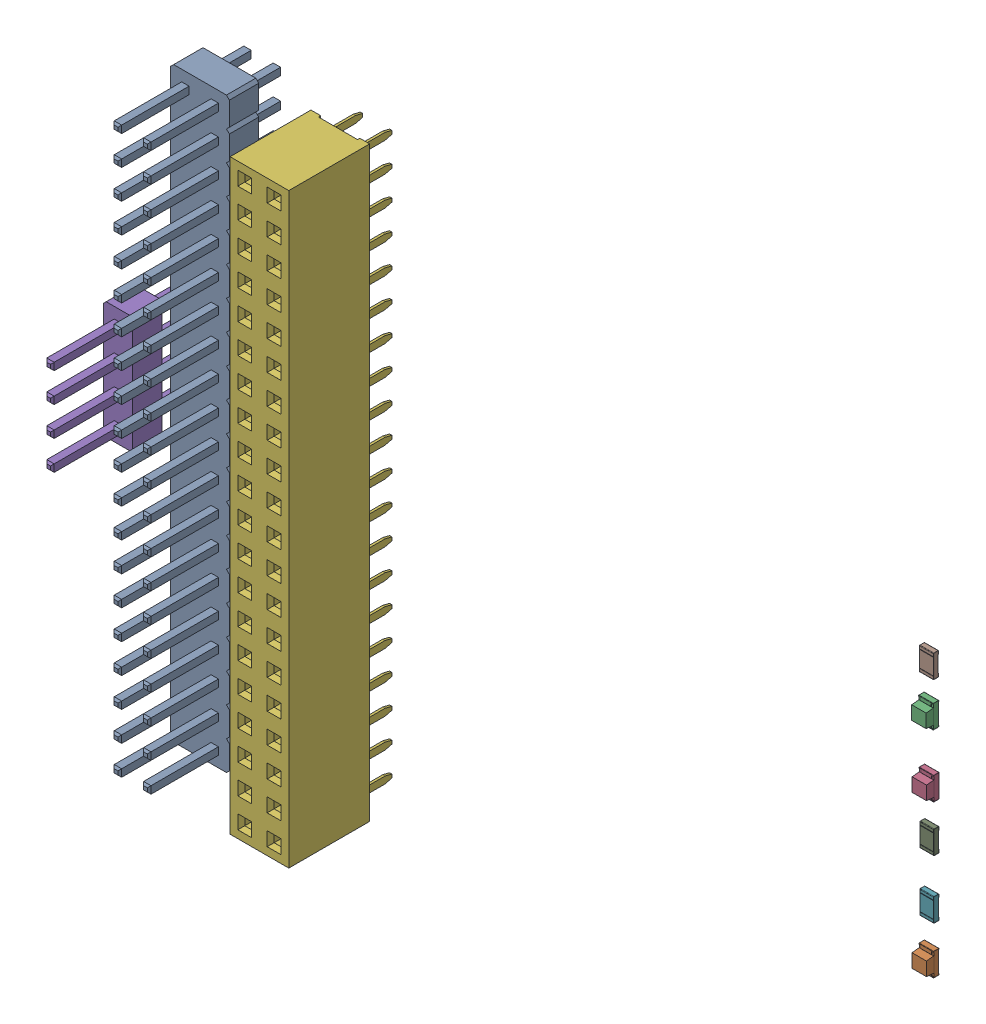
SolidWorks assembly Top, configuration 默认. Lengths in mm.
Overall size (69.83 50.8 11.64).
9 component instances, 9 part files, 0 mates.
Components (placement in the parent):
- J6_PinHeader_2x20_P254mm_Vertical_5E973953-1: J6_PinHeader_2x20_P254mm_Vertical_5E973953 [默认] at (34.12 74.135 0) size (5.08 50.8 11.54)
- D1_LED_0805_2012Metric_5E97381B-1: D1_LED_0805_2012Metric_5E97381B [默认] at (96.209 38.751 0) x (0 1 0) z (0 0 1) size (2 1.25 1.1)
- D3_LED_0805_2012Metric_5E973846-1: D3_LED_0805_2012Metric_5E973846 [默认] at (96.182 57.3275 0) x (0 1 0) z (0 0 1) size (2 1.25 1.1)
- D5_LED_0805_2012Metric_5E973871-1: D5_LED_0805_2012Metric_5E973871 [默认] at (96.218 51.946 0) x (0 -1 0) z (0 0 1) size (2 1.25 1.1)
- J2_PinHeader_1x04_P254mm_Vertical_5E9738C1-1: J2_PinHeader_1x04_P254mm_Vertical_5E9738C1 [默认] at (28.278 53.434 0) size (2.54 10.16 11.54)
- J5_PinSocket_2x20_P254mm_Vertical_5E975A58-1: J5_PinSocket_2x20_P254mm_Vertical_5E975A58 [默认] at (46.26 74.13 0) size (5.08 50.8 10.1)
- R4_R_0805_2012Metric_5E99E94D-1: R4_R_0805_2012Metric_5E99E94D [默认] at (96.209 42.815 0) x (0 -1 0) z (0 0 1) size (2 1.2 0.45)
- R18_R_0805_2012Metric_5E9C048F-1: R18_R_0805_2012Metric_5E9C048F [默认] at (96.182 61.059 0) x (0 -1 0) z (0 0 1) size (2 1.2 0.45)
- R21_R_0805_2012Metric_5E973B6B-1: R21_R_0805_2012Metric_5E973B6B [默认] at (96.218 47.882 0) x (0 -1 0) z (0 0 1) size (2 1.2 0.45)
